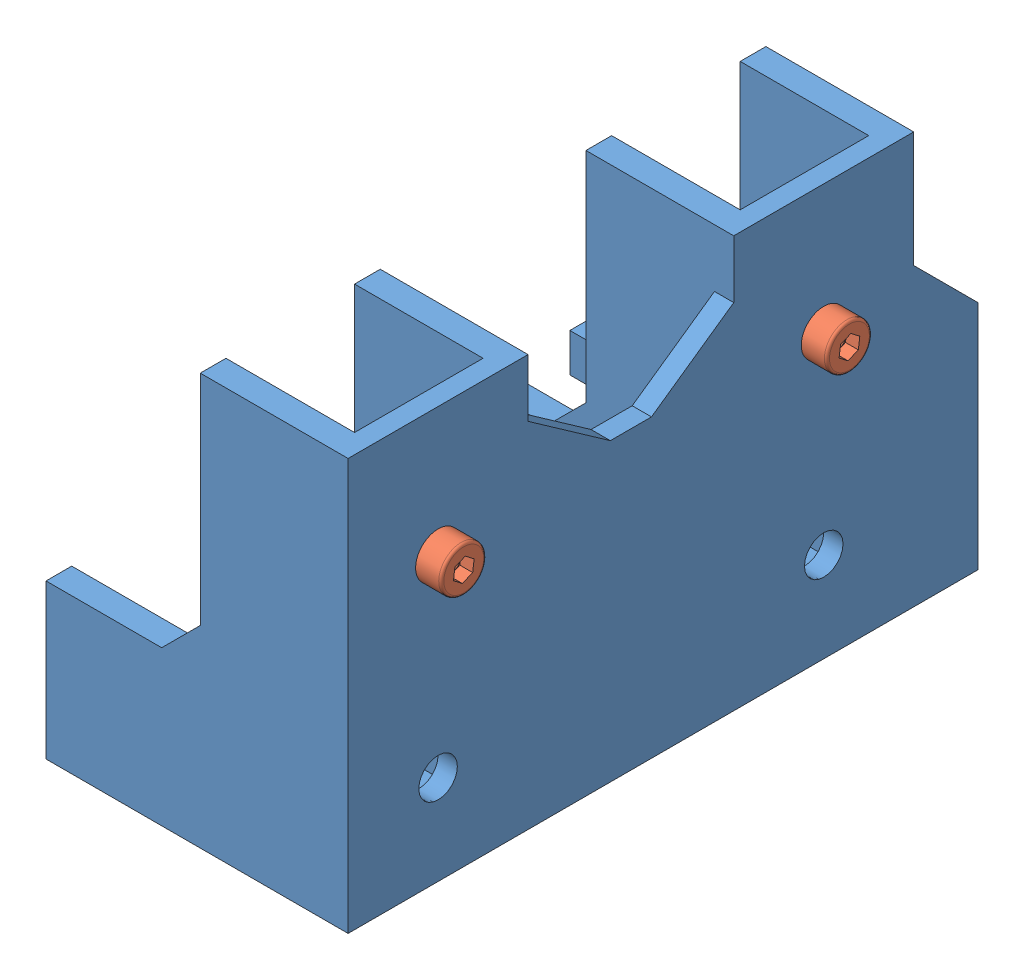
SolidWorks assembly FootCorner, configuration Défaut. Lengths in mm.
Overall size (51 68 98).
9 component instances, 3 part files, 19 mates.
Components (placement in the parent):
- foot front right-1: foot front right [Défaut] at (0 -9.6009 -0.4682) size (47 64 98)
- socket head cap screw_din2-1: socket head cap screw_din2 [DIN 912 M4 x 8 --- 8C] at (-27 -468.759 83.5318) x (0 1 0) z (0 0 1) size (12 7 7)
- socket head cap screw_din2-2: socket head cap screw_din2 [DIN 912 M4 x 8 --- 8C] at (-27 -468.759 23.5318) x (0 1 0) z (0 0 1) size (12 7 7)
- socket head cap screw_din2-3: socket head cap screw_din2 [DIN 912 M4 x 8 --- 8C] at (4 -420.759 23.5318) x (-1 0 0) z (0 0.924225 0.381849) size (12 7 7)
- socket head cap screw_din2-4: socket head cap screw_din2 [DIN 912 M4 x 8 --- 8C] at (4 -420.759 83.5318) x (-1 0 0) z (0 0.924225 0.381849) size (12 7 7)
- 8020-14164-1: 8020-14164 [Default] at (-27 -455.059 21.2818) x (-1 0 0) z (0 0 1) size (5.7 5.7 11.5)
- 8020-14164-2: 8020-14164 [Default] at (-8.7 -420.759 81.2818) x (0 -1 0) z (0 0 1) size (5.7 5.7 11.5)
- 8020-14164-3: 8020-14164 [Default] at (-8.7 -420.759 21.2818) x (0 -1 0) z (0 0 1) size (5.7 5.7 11.5)
- 8020-14164-4: 8020-14164 [Default] at (-27 -455.059 81.2818) x (-1 0 0) z (0 0 1) size (5.7 5.7 11.5)
Mates (geometry in assembly coordinates):
- Coaxiale2: concentric anti-aligned: cylinder of foot front right-1 through (-27 -464.7591 83.5318) axis (0 1 0) radius 2.1; cylinder of socket head cap screw_din2-1 through (-27 -500.509 83.5318) axis (0 -1 0) radius 3.5
- Coïncidente2: coincident anti-aligned: plane of foot front right-1 through (-3 -464.759 -0.4682) normal (0 -1 0); plane of socket head cap screw_din2-1 through (-30.5 -464.759 83.5318) normal (0 1 0)
- Coaxiale3: concentric anti-aligned: cylinder of foot front right-1 through (-27 -464.7591 23.5318) axis (0 1 0) radius 2.1; cylinder of socket head cap screw_din2-2 through (-27 -500.509 23.5318) axis (0 -1 0) radius 3.5
- Coïncidente3: coincident anti-aligned: plane of foot front right-1 through (-3 -464.759 -0.4682) normal (0 -1 0); plane of socket head cap screw_din2-2 through (-30.5 -464.759 23.5318) normal (0 1 0)
- Coaxiale4: concentric anti-aligned: cylinder of foot front right-1 through (0 -420.759 83.5318) axis (-1 0 0) radius 2.1; cylinder of socket head cap screw_din2-4 through (35.75 -420.759 83.5318) axis (1 0 0) radius 3.5
- Coïncidente4: coincident anti-aligned: plane of foot front right-1 through (0 -9.6009 -0.4682) normal (1 0 0); plane of socket head cap screw_din2-4 through (0 -422.0955 86.7665) normal (-1 0 0)
- Parallèle1: parallel aligned: plane of foot front right-1 through (-47 -9.6009 -0.4682) normal (-1 0 0); plane of 8020-14164-1 through (-29.85 -459.559 23.2285) normal (-1 0 0)
- Coaxiale8: concentric anti-aligned: cylinder of foot front right-1 through (0 -420.759 23.5318) axis (-1 0 0) radius 2.1; cylinder of socket head cap screw_din2-3 through (35.75 -420.759 23.5318) axis (1 0 0) radius 2
- Coïncidente11: coincident anti-aligned: plane of foot front right-1 through (0 -9.6009 -0.4682) normal (1 0 0); plane of socket head cap screw_din2-3 through (0 -422.0955 26.7665) normal (-1 0 0)
- Parallèle2: parallel aligned: plane of foot front right-1 through (-3 -400.759 97.5318) normal (0 1 0); plane of 8020-14164-2 through (-4.2 -417.909 83.2285) normal (0 1 0)
- Parallèle3: parallel aligned: plane of foot front right-1 through (-47 -9.6009 -0.4682) normal (-1 0 0); plane of 8020-14164-4 through (-29.85 -459.559 83.2285) normal (-1 0 0)
- Coaxiale9: concentric anti-aligned: cylinder of socket head cap screw_din2-4 through (35.75 -420.759 83.5318) axis (1 0 0) radius 2; cylinder of 8020-14164-2 through (-3 -420.759 83.5318) axis (-1 0 0) radius 2
- Coïncidente12: coincident anti-aligned: plane of foot front right-1 through (-3 -9.6009 -0.4682) normal (-1 0 0); plane of 8020-14164-2 through (-3 -420.109 84.0818) normal (1 0 0)
- Coaxiale10: concentric anti-aligned: cylinder of socket head cap screw_din2-1 through (-27 -500.509 83.5318) axis (0 -1 0) radius 2; cylinder of 8020-14164-4 through (-27 -460.759 83.5318) axis (0 1 0) radius 2
- Coïncidente14: coincident anti-aligned: plane of foot front right-1 through (-47 -460.759 93.5318) normal (0 1 0); plane of 8020-14164-4 through (-26.35 -460.759 84.0818) normal (0 -1 0)
- Coïncidente15: coincident anti-aligned: plane of foot front right-1 through (-47 -460.759 33.5318) normal (0 1 0); plane of 8020-14164-1 through (-26.35 -460.759 24.0818) normal (0 -1 0)
- Coaxiale11: concentric anti-aligned: cylinder of socket head cap screw_din2-2 through (-27 -500.509 23.5318) axis (0 -1 0) radius 2; cylinder of 8020-14164-1 through (-27 -460.759 23.5318) axis (0 1 0) radius 2
- Coaxiale12: concentric anti-aligned: cylinder of socket head cap screw_din2-3 through (35.75 -420.759 23.5318) axis (1 0 0) radius 2; cylinder of 8020-14164-3 through (-3 -420.759 23.5318) axis (-1 0 0) radius 2
- Coïncidente17: coincident anti-aligned: plane of foot front right-1 through (-3 -9.6009 -0.4682) normal (-1 0 0); plane of 8020-14164-3 through (-3 -420.109 24.0818) normal (1 0 0)
